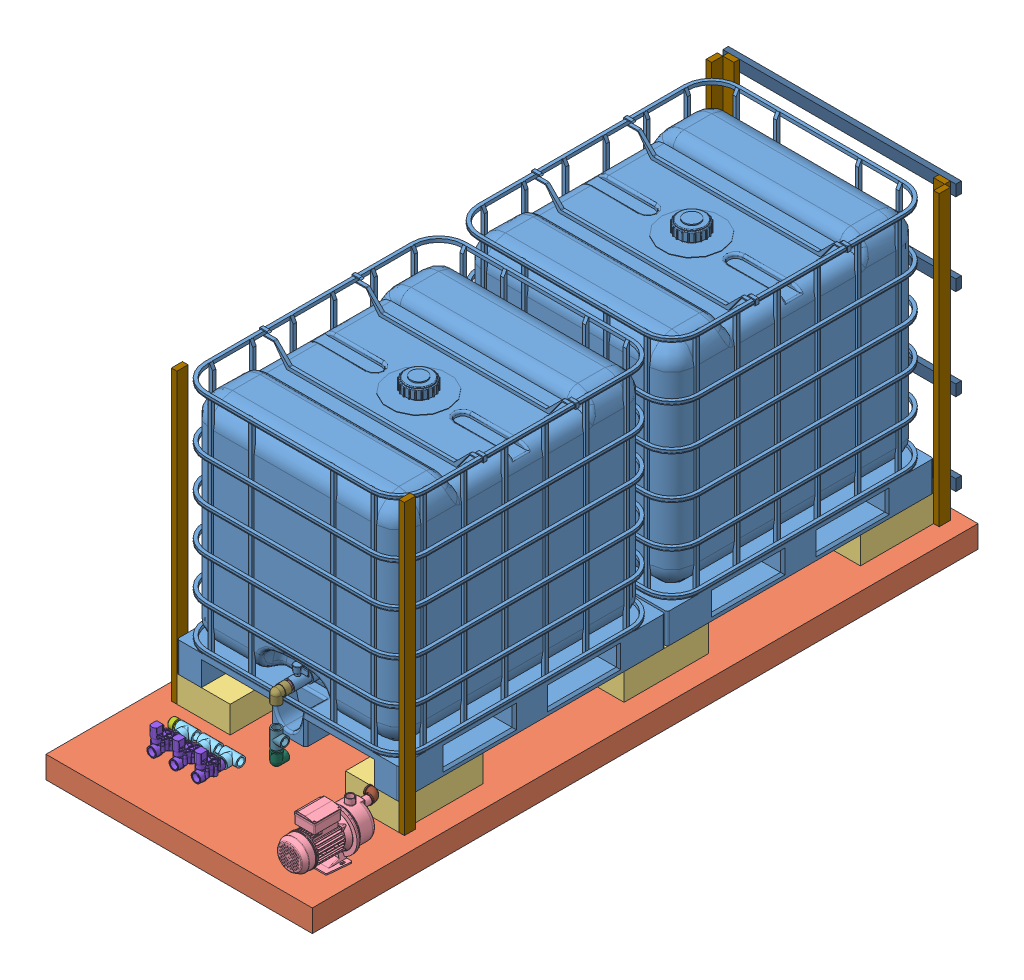
SolidWorks assembly zlozony_zbiornik, configuration Domyślna. Lengths in mm.
Overall size (1200 1400 3000).
43 component instances, 15 part files, 91 mates.
Components (placement in the parent):
- zbiornik_1000L-3: zbiornik_1000L [Domyślna] at (-84.7782 -19.1677 1200.0339) size (1010 1160 1200.03)
- zbiornik_1000L-4: zbiornik_1000L [Domyślna] at (-68.0731 -19.1677 -237.8252) x (-1 0 0) z (0 0 -1) size (1010 1160 1200.03)
- podstawa_zbiornikow-1: podstawa_zbiornikow [Domyślna] at (-76.4256 -772.0394 676.1044) x (0 0 -1) z (1 0 0) size (3000 100 1200)
- bloczek_fundamentowy-1: bloczek_fundamentowy [Domyślna] at (-456.4256 -672.0394 -583.8956) x (0 0 -1) z (1 0 0) size (380 120 240)
- bloczek_fundamentowy-2: bloczek_fundamentowy [Domyślna] at (303.5744 -672.0394 -583.8956) x (0 0 -1) z (1 0 0) size (380 120 240)
- bloczek_fundamentowy-3: bloczek_fundamentowy [Domyślna] at (303.5744 -672.0394 1496.1044) x (0 0 -1) z (1 0 0) size (380 120 240)
- bloczek_fundamentowy-4: bloczek_fundamentowy [Domyślna] at (303.5744 -672.0394 481.1044) x (0 0 -1) z (1 0 0) size (380 120 240)
- bloczek_fundamentowy-5: bloczek_fundamentowy [Domyślna] at (-456.4256 -672.0394 1496.1044) x (0 0 -1) z (1 0 0) size (380 120 240)
- bloczek_fundamentowy-6: bloczek_fundamentowy [Domyślna] at (-456.4256 -672.0394 481.1044) x (0 0 -1) z (1 0 0) size (380 120 240)
- WJ 202-x-1: WJ 202-x [Default] at (373.8254 -573.0394 1909.6044) x (0 0 1) z (-1 0 0) size (354 228.5 184)
- Trojnik_32_gz1-1: Trojnik_32_gz1 [Default] at (-94.2256 -519.8394 1919.1044) x (0 0 1) z (-1 0 0) size (88 48 77)
  - 300125171_01-1: 300125171_01 [Default] at origin size (68 48 77)
  - 300125171_02-1: 300125171_02 [Default] at origin size (38 43 43)
- Trojnik_32_gz1-2: Trojnik_32_gz1 [Default] at (-194.2256 -519.8394 1919.1044) x (0 0 1) z (-1 0 0) size (88 48 77)
  - 300125171_01-1: 300125171_01 [Default] at origin size (68 48 77)
  - 300125171_02-1: 300125171_02 [Default] at origin size (38 43 43)
- Trojnik_32_gz1-3: Trojnik_32_gz1 [Default] at (-294.2256 -519.8394 1919.1044) x (0 0 1) z (-1 0 0) size (88 48 77)
  - 300125171_01-1: 300125171_01 [Default] at origin size (68 48 77)
  - 300125171_02-1: 300125171_02 [Default] at origin size (38 43 43)
- zaslepka_32-1: zaslepka_32 [Default] at (-342.7256 -519.8394 1919.1044) size (31 43 43)
- DV100-1: DV100 [Domyślna] at (-94.2256 -519.8394 2028.1044) x (0 0 -1) z (1 0 0) size (113 119.31 83.38)
- DV100-2: DV100 [Domyślna] at (-194.2256 -519.8394 2028.1044) x (0 0 -1) z (1 0 0) size (113 119.31 83.38)
- DV100-3: DV100 [Domyślna] at (-294.2256 -519.8394 2028.1044) x (0 0 -1) z (1 0 0) size (113 119.31 83.38)
- Łata25x50^zlozony_zbiornik-1: Łata25x50^zlozony_zbiornik [Domyślna] at (-56.8231 -672.0394 651.9457) x (0 0 -1) z (0 1 0) size (25 50 1300) (virtual)
- Łata25x50^zlozony_zbiornik-2: Łata25x50^zlozony_zbiornik [Domyślna] at (893.1769 -672.0394 651.9457) x (0 0 -1) z (0 1 0) size (25 50 1300) (virtual)
- Łata25x50^zlozony_zbiornik-3: Łata25x50^zlozony_zbiornik [Domyślna] at (-1002.267 -672.0394 -254.2931) x (1 0 0) z (0 1 0) size (25 50 1300) (virtual)
- Łata25x50^zlozony_zbiornik-4: Łata25x50^zlozony_zbiornik [Domyślna] at (-2027.267 -672.0394 -254.2931) x (1 0 0) z (0 1 0) size (25 50 1300) (virtual)
- Łata25x50_pozioma^zlozony_zbiornik-1: Łata25x50_pozioma^zlozony_zbiornik [Domyślna] at (893.1769 -672.0394 -798.8956) x (0 -1 0) z (0 0 -1) size (50 1050 25) (virtual)
- Łata25x50_pozioma^zlozony_zbiornik-2: Łata25x50_pozioma^zlozony_zbiornik [Domyślna] at (893.1769 -302.0394 -798.8956) x (0 -1 0) z (0 0 -1) size (50 1050 25) (virtual)
- Łata25x50_pozioma^zlozony_zbiornik-3: Łata25x50_pozioma^zlozony_zbiornik [Domyślna] at (893.1769 107.9606 -798.8956) x (0 -1 0) z (0 0 -1) size (50 1050 25) (virtual)
- Łata25x50_pozioma^zlozony_zbiornik-4: Łata25x50_pozioma^zlozony_zbiornik [Domyślna] at (893.1769 477.9606 -798.8956) x (0 -1 0) z (0 0 -1) size (50 1050 25) (virtual)
- Łata25x50^zlozony_zbiornik-5: Łata25x50^zlozony_zbiornik [Domyślna] at (849.4157 -672.0394 1166.5018) x (-1 0 0) z (0 1 0) size (25 50 1300) (virtual)
- Łata25x50^zlozony_zbiornik-6: Łata25x50^zlozony_zbiornik [Domyślna] at (-1002.267 -672.0394 2155.7069) x (1 0 0) z (0 1 0) size (25 50 1300) (virtual)
- 90° Elbow G 1 SS-2: 90° Elbow G 1 SS [Default] at (335.8254 -524.5394 1737.6044) x (0 0 1) z (0 1 0) size (59.19 59.2 40.8)
- kolano_32_gz1-2: kolano_32_gz1 [Default] at (-76.4256 -388.5394 1737.6044) x (0 0 -1) z (0 1 0) size (88 48 60.5)
  - 300125158_01-1: 300125158_01 [Default] at origin size (68 48 60.5)
  - 300125158_02-1: 300125158_02 [Default] at origin size (38 43 43)
- trojnik_32-3: trojnik_32 [Default] at (-76.4256 -524.5394 1737.6044) x (1 0 0) z (0 1 0) size (60 43 77)
- kolano_32_gz1-3: kolano_32_gz1 [Default] at (-76.4256 -388.5394 -775.3956) x (0 0 1) z (0 1 0) size (88 48 60.5)
  - 300125158_01-1: 300125158_01 [Default] at origin size (68 48 60.5)
  - 300125158_02-1: 300125158_02 [Default] at origin size (38 43 43)
- kolano_32-9: kolano_32 [Default] at (-76.4256 -574.8405 -775.3956) x (0 0 1) z (0 -1 0) size (59.8 43.6 59.8)
- kolano_32-10: kolano_32 [Default] at (-76.4256 -612.8405 1699.6044) x (0 1 0) z (0 0 1) size (59.8 43.6 59.8)
Mates (geometry in assembly coordinates):
- Wspólnie21: coincident anti-aligned: plane of podstawa_zbiornikow-1 through (-76.4256 -672.0394 676.1044) normal (0 1 0); plane of bloczek_fundamentowy-5 through (-456.4256 -672.0394 1496.1044) normal (0 -1 0)
- Wspólnie25: coincident anti-aligned: plane of podstawa_zbiornikow-1 through (-76.4256 -672.0394 676.1044) normal (0 1 0); plane of bloczek_fundamentowy-1 through (-456.4256 -672.0394 -583.8956) normal (0 -1 0)
- Wspólnie26: coincident anti-aligned: plane of podstawa_zbiornikow-1 through (-76.4256 -672.0394 676.1044) normal (0 1 0); plane of bloczek_fundamentowy-6 through (-456.4256 -672.0394 481.1044) normal (0 -1 0)
- Wspólnie27: coincident anti-aligned: plane of podstawa_zbiornikow-1 through (-76.4256 -672.0394 676.1044) normal (0 1 0); plane of bloczek_fundamentowy-5 through (-456.4256 -672.0394 1496.1044) normal (0 -1 0)
- Wspólnie28: coincident anti-aligned: plane of podstawa_zbiornikow-1 through (-76.4256 -672.0394 676.1044) normal (0 1 0); plane of bloczek_fundamentowy-2 through (303.5744 -672.0394 -583.8956) normal (0 -1 0)
- Wspólnie29: coincident anti-aligned: plane of podstawa_zbiornikow-1 through (-76.4256 -672.0394 676.1044) normal (0 1 0); plane of bloczek_fundamentowy-4 through (303.5744 -672.0394 481.1044) normal (0 -1 0)
- Wspólnie30: coincident anti-aligned: plane of podstawa_zbiornikow-1 through (-76.4256 -672.0394 676.1044) normal (0 1 0); plane of bloczek_fundamentowy-3 through (303.5744 -672.0394 1496.1044) normal (0 -1 0)
- Szerokość1: width anti-aligned: plane of podstawa_zbiornikow-1 through (523.5744 -672.0394 2176.1044) normal (1 0 0); plane of podstawa_zbiornikow-1 through (-676.4256 -672.0394 2176.1044) normal (-1 0 0); plane of zbiornik_1000L-1/zbiornik_1000L.stp-1/PALLET.stp-1 through (-576.4256 -417.0394 486.1044) normal (-1 0 0); plane of zbiornik_1000L-1/zbiornik_1000L.stp-1/PALLET.stp-1 through (423.5744 -552.0394 486.1044) normal (1 0 0)
- Wspólnie31: coincident anti-aligned: plane of bloczek_fundamentowy-4 through (303.5744 -552.0394 481.1044) normal (0 1 0); plane of zbiornik_1000L-1/zbiornik_1000L.stp-1/PALLET.stp-1 through (-576.4256 -552.0394 486.1044) normal (0 -1 0)
- Wspólnie32: coincident aligned: plane of bloczek_fundamentowy-4 through (423.5744 -552.0394 671.1044) normal (1 0 0); plane of zbiornik_1000L-1/zbiornik_1000L.stp-1/PALLET.stp-1 through (423.5744 -552.0394 486.1044) normal (1 0 0)
- Wspólnie34: coincident aligned: plane of bloczek_fundamentowy-3 through (423.5744 -552.0394 1686.1044) normal (1 0 0); plane of zbiornik_1000L-1/zbiornik_1000L.stp-1/PALLET.stp-1 through (423.5744 -552.0394 486.1044) normal (1 0 0)
- Wspólnie35: coincident aligned: plane of bloczek_fundamentowy-3 through (423.5744 -552.0394 1686.1044) normal (0 0 1); plane of zbiornik_1000L-1/zbiornik_1000L.stp-1/PALLET.stp-1 through (-76.4256 -484.5394 1686.1044) normal (0 0 1)
- Wspólnie39: coincident aligned: plane of bloczek_fundamentowy-6 through (-576.4256 -552.0394 671.1044) normal (-1 0 0); plane of zbiornik_1000L-1/zbiornik_1000L.stp-1/PALLET.stp-1 through (-576.4256 -417.0394 486.1044) normal (-1 0 0)
- Wspólnie40: coincident aligned: plane of bloczek_fundamentowy-5 through (-576.4256 -552.0394 1686.1044) normal (-1 0 0); plane of zbiornik_1000L-1/zbiornik_1000L.stp-1/PALLET.stp-1 through (-576.4256 -417.0394 486.1044) normal (-1 0 0)
- Wspólnie41: coincident aligned: plane of bloczek_fundamentowy-5 through (-336.4256 -552.0394 1686.1044) normal (0 0 1); plane of zbiornik_1000L-1/zbiornik_1000L.stp-1/PALLET.stp-1 through (-76.4256 -484.5394 1686.1044) normal (0 0 1)
- Odległość15: distance = 50 mm aligned: plane of bloczek_fundamentowy-2 through (423.5744 -552.0394 -773.8956) normal (0 0 -1); plane of podstawa_zbiornikow-1 through (523.5744 -672.0394 -823.8956) normal (0 0 -1)
- Koncentryczne35: concentric aligned: cylinder of Trojnik_32_gz1-1/300125171_01-1 through (-94.2256 -519.8394 1919.1044) axis (1 0 0) radius 22; cylinder of Trojnik_32_gz1-2/300125171_01-1 through (-194.2256 -519.8394 1919.1044) axis (1 0 0) radius 22
- Odległość25: distance = 100 mm: cylinder of Trojnik_32_gz1-2/300125171_02-1 through (-194.2256 -519.8394 1975.1044) axis (0 0 -1) radius 16.625; cylinder of Trojnik_32_gz1-1/300125171_02-1 through (-94.2256 -519.8394 1975.1044) axis (0 0 -1) radius 16.625
- Koncentryczne37: concentric aligned: cylinder of Trojnik_32_gz1-2/300125171_01-1 through (-194.2256 -519.8394 1919.1044) axis (1 0 0) radius 22; cylinder of Trojnik_32_gz1-3/300125171_01-1 through (-294.2256 -519.8394 1919.1044) axis (1 0 0) radius 22
- Odległość26: distance = 100 mm: cylinder of Trojnik_32_gz1-2/300125171_02-1 through (-194.2256 -519.8394 1975.1044) axis (0 0 -1) radius 16.625; cylinder of Trojnik_32_gz1-3/300125171_02-1 through (-294.2256 -519.8394 1975.1044) axis (0 0 -1) radius 16.625
- Koncentryczne39: concentric aligned: cylinder of Trojnik_32_gz1-3/300125171_01-1 through (-294.2256 -519.8394 1919.1044) axis (1 0 0) radius 22; cylinder of zaslepka_32-1 through (-352.7256 -519.8394 1919.1044) axis (1 0 0) radius 21.5
- Odległość27: distance = 10 mm anti-aligned: plane of Trojnik_32_gz1-3/300125171_01-1 through (-332.7256 -519.8394 1919.1044) normal (-1 0 0); plane of zaslepka_32-1 through (-342.7256 -519.8394 1919.1044) normal (1 0 0)
- Wspólnie42: coincident anti-aligned: plane of zbiornik_1000L-3 through (-576.4256 -552.0394 486.1044) normal (0 -1 0); plane of bloczek_fundamentowy-5 through (-456.4256 -552.0394 1496.1044) normal (0 1 0)
- Wspólnie44: coincident aligned: plane of zbiornik_1000L-3 through (-576.4256 -417.0394 486.1044) normal (-1 0 0); plane of bloczek_fundamentowy-6 through (-576.4256 -552.0394 671.1044) normal (-1 0 0)
- Wspólnie45: coincident aligned: plane of zbiornik_1000L-3 through (423.5744 -552.0394 486.1044) normal (1 0 0); plane of bloczek_fundamentowy-4 through (423.5744 -552.0394 671.1044) normal (1 0 0)
- Odległość28: distance = 10 mm anti-aligned: plane of zbiornik_1000L-3 through (-76.4256 -484.5394 486.1044) normal (0 0 -1); plane of zbiornik_1000L-4 through (-76.4256 -484.5394 476.1044) normal (0 0 1)
- Wspólnie46: coincident aligned: plane of zbiornik_1000L-3 through (423.5744 -552.0394 486.1044) normal (1 0 0); plane of zbiornik_1000L-4 through (423.5744 -417.0394 476.1044) normal (1 0 0)
- Wspólnie47: coincident aligned: plane of zbiornik_1000L-4 through (423.5744 -417.0394 476.1044) normal (1 0 0); plane of bloczek_fundamentowy-4 through (423.5744 -552.0394 671.1044) normal (1 0 0)
- Szerokość6: width anti-aligned: plane of zbiornik_1000L-3 through (423.5744 -442.0394 696.1044) normal (0 0 1); plane of zbiornik_1000L-4 through (-576.4256 -442.0394 266.1044) normal (0 0 -1); plane of bloczek_fundamentowy-4 through (423.5744 -552.0394 291.1044) normal (0 0 -1); plane of bloczek_fundamentowy-4 through (423.5744 -552.0394 671.1044) normal (0 0 1)
- Wspólnie49: coincident anti-aligned: plane of zbiornik_1000L-4 through (423.5744 -552.0394 476.1044) normal (0 -1 0); plane of bloczek_fundamentowy-4 through (303.5744 -552.0394 481.1044) normal (0 1 0)
- Wspólnie50: coincident aligned: plane of zbiornik_1000L-3 through (-76.4256 -484.5394 1686.1044) normal (0 0 1); plane of bloczek_fundamentowy-5 through (-336.4256 -552.0394 1686.1044) normal (0 0 1)
- Wspólnie51: coincident aligned: plane of zbiornik_1000L-3 through (-76.4256 -484.5394 1686.1044) normal (0 0 1); plane of bloczek_fundamentowy-3 through (423.5744 -552.0394 1686.1044) normal (0 0 1)
- Szerokość7: width anti-aligned: plane of zbiornik_1000L-3 through (423.5744 -442.0394 696.1044) normal (0 0 1); plane of zbiornik_1000L-4 through (-576.4256 -442.0394 266.1044) normal (0 0 -1); plane of bloczek_fundamentowy-6 through (-336.4256 -552.0394 291.1044) normal (0 0 -1); plane of bloczek_fundamentowy-6 through (-336.4256 -552.0394 671.1044) normal (0 0 1)
- Wspólnie53: coincident aligned: plane of zbiornik_1000L-3 through (-576.4256 -417.0394 486.1044) normal (-1 0 0); plane of bloczek_fundamentowy-5 through (-576.4256 -552.0394 1686.1044) normal (-1 0 0)
- Wspólnie54: coincident aligned: plane of zbiornik_1000L-4 through (-576.4256 -552.0394 476.1044) normal (-1 0 0); plane of bloczek_fundamentowy-1 through (-576.4256 -552.0394 -393.8956) normal (-1 0 0)
- Wspólnie57: coincident aligned: plane of zbiornik_1000L-4 through (423.5744 -417.0394 476.1044) normal (1 0 0); plane of bloczek_fundamentowy-2 through (423.5744 -552.0394 -393.8956) normal (1 0 0)
- Wspólnie58: coincident aligned: plane of zbiornik_1000L-3 through (423.5744 -552.0394 486.1044) normal (1 0 0); plane of bloczek_fundamentowy-3 through (423.5744 -552.0394 1686.1044) normal (1 0 0)
- Wspólnie59: coincident aligned: plane of zbiornik_1000L-3 through (-76.4256 -484.5394 1686.1044) normal (0 0 1); plane of bloczek_fundamentowy-3 through (423.5744 -552.0394 1686.1044) normal (0 0 1)
- Szerokość8: width anti-aligned: plane of podstawa_zbiornikow-1 through (523.5744 -672.0394 2176.1044) normal (1 0 0); plane of podstawa_zbiornikow-1 through (-676.4256 -672.0394 2176.1044) normal (-1 0 0); plane of bloczek_fundamentowy-1 through (-576.4256 -552.0394 -393.8956) normal (-1 0 0); plane of bloczek_fundamentowy-2 through (423.5744 -552.0394 -393.8956) normal (1 0 0)
- Koncentryczne42: concentric anti-aligned: cylinder of Trojnik_32_gz1-1/300125171_02-1 through (-94.2256 -519.8394 1975.1044) axis (0 0 -1) radius 16.625; cylinder of DV100-1 through (-94.2256 -519.8394 3028.1044) axis (0 0 1) radius 21.463
- Odległość31: distance = 5 mm anti-aligned: plane of Trojnik_32_gz1-1/300125171_01-1 through (-94.2256 -519.8394 1965.1044) normal (0 0 1); plane of DV100-1 through (-94.2256 -519.8394 1970.1044) normal (0 0 -1)
- Koncentryczne43: concentric anti-aligned: cylinder of Trojnik_32_gz1-2/300125171_02-1 through (-194.2256 -519.8394 1975.1044) axis (0 0 -1) radius 16.625; cylinder of DV100-2 through (-194.2256 -519.8394 3028.1044) axis (0 0 1) radius 21.463
- Koncentryczne44: concentric anti-aligned: cylinder of Trojnik_32_gz1-3/300125171_02-1 through (-294.2256 -519.8394 1975.1044) axis (0 0 -1) radius 16.625; cylinder of DV100-3 through (-294.2256 -519.8394 3028.1044) axis (0 0 1) radius 21.463
- Odległość32: distance = 5 mm anti-aligned: plane of DV100-2 through (-194.2256 -519.8394 1970.1044) normal (0 0 -1); plane of Trojnik_32_gz1-2/300125171_01-1 through (-194.2256 -519.8394 1965.1044) normal (0 0 1)
- Odległość33: distance = 5 mm anti-aligned: plane of Trojnik_32_gz1-3/300125171_01-1 through (-294.2256 -519.8394 1965.1044) normal (0 0 1); plane of DV100-3 through (-294.2256 -519.8394 1970.1044) normal (0 0 -1)
- Wspólnie63: coincident anti-aligned: plane of podstawa_zbiornikow-1 through (-76.4256 -672.0394 676.1044) normal (0 1 0); plane of Łata25x50^zlozony_zbiornik-2 through (893.1769 -672.0394 651.9457) normal (0 -1 0)
- Wspólnie64: coincident anti-aligned: plane of bloczek_fundamentowy-2 through (423.5744 -552.0394 -773.8956) normal (0 0 -1); plane of Łata25x50^zlozony_zbiornik-2 through (373.5744 627.9606 -773.8956) normal (0 0 1)
- Wspólnie65: coincident aligned: plane of bloczek_fundamentowy-2 through (423.5744 -552.0394 -393.8956) normal (1 0 0); plane of Łata25x50^zlozony_zbiornik-2 through (423.5744 627.9606 -773.8956) normal (1 0 0)
- Wspólnie67: coincident anti-aligned: plane of bloczek_fundamentowy-1 through (-336.4256 -552.0394 -773.8956) normal (0 0 -1); plane of Łata25x50^zlozony_zbiornik-1 through (-576.4256 627.9606 -773.8956) normal (0 0 1)
- Wspólnie68: coincident anti-aligned: plane of podstawa_zbiornikow-1 through (-76.4256 -672.0394 676.1044) normal (0 1 0); plane of Łata25x50^zlozony_zbiornik-1 through (-56.8231 -672.0394 651.9457) normal (0 -1 0)
- Wspólnie69: coincident aligned: plane of bloczek_fundamentowy-1 through (-576.4256 -552.0394 -393.8956) normal (-1 0 0); plane of Łata25x50^zlozony_zbiornik-1 through (-576.4256 627.9606 -773.8956) normal (-1 0 0)
- Wspólnie70: coincident anti-aligned: plane of bloczek_fundamentowy-2 through (423.5744 -552.0394 -393.8956) normal (1 0 0); plane of Łata25x50^zlozony_zbiornik-3 through (423.5744 627.9606 -773.8956) normal (-1 0 0)
- Wspólnie71: coincident anti-aligned: plane of podstawa_zbiornikow-1 through (-76.4256 -672.0394 676.1044) normal (0 1 0); plane of Łata25x50^zlozony_zbiornik-3 through (-1002.267 -672.0394 -254.2931) normal (0 -1 0)
- Wspólnie72: coincident aligned: plane of bloczek_fundamentowy-2 through (423.5744 -552.0394 -773.8956) normal (0 0 -1); plane of Łata25x50^zlozony_zbiornik-3 through (423.5744 627.9606 -773.8956) normal (0 0 -1)
- Wspólnie73: coincident anti-aligned: plane of bloczek_fundamentowy-1 through (-576.4256 -552.0394 -393.8956) normal (-1 0 0); plane of Łata25x50^zlozony_zbiornik-4 through (-576.4256 627.9606 -773.8956) normal (1 0 0)
- Wspólnie74: coincident anti-aligned: plane of podstawa_zbiornikow-1 through (-76.4256 -672.0394 676.1044) normal (0 1 0); plane of Łata25x50^zlozony_zbiornik-4 through (-2027.267 -672.0394 -254.2931) normal (0 -1 0)
- Wspólnie75: coincident aligned: plane of bloczek_fundamentowy-1 through (-336.4256 -552.0394 -773.8956) normal (0 0 -1); plane of Łata25x50^zlozony_zbiornik-4 through (-601.4256 627.9606 -773.8956) normal (0 0 -1)
- Ustalone8: in place: plane of ? through (373.5744 627.9606 -748.8956) normal (0 0 -1); plane of ? through (0 0 -748.8956) normal (0 0 -1); moOrthogonalPlaneRef_w of ? through (373.5744 627.9606 -748.8956) normal (0 0 -1); plane of ? through (0 0 -748.8956) normal (0 1 0); plane of ? through (373.5744 627.9606 -748.8956) normal (0 0 -1); plane of ? through (0 0 -748.8956) normal (-1 0 0); plane of Łata25x50^zlozony_zbiornik-2 through (373.5744 627.9606 -798.8956) normal (0 0 -1); unknown of Łata25x50_pozioma^zlozony_zbiornik-1
- Wspólnie76: coincident aligned: plane of Łata25x50^zlozony_zbiornik-2; plane of Łata25x50_pozioma^zlozony_zbiornik-1
- Wspólnie77: coincident aligned: moOrthogonalPlaneRef_w of Łata25x50^zlozony_zbiornik-2 through (893.1769 -672.0394 -798.8956) normal (-1 0 0); plane of Łata25x50_pozioma^zlozony_zbiornik-1 through (893.1769 -672.0394 -798.8956) normal (-1 0 0)
- Wspólnie78: coincident anti-aligned: moOrthogonalPlaneRef_w of Łata25x50^zlozony_zbiornik-2 through (893.1769 -672.0394 -798.8956) normal (0 1 0); plane of Łata25x50_pozioma^zlozony_zbiornik-1 through (893.1769 -672.0394 -798.8956) normal (0 -1 0)
- Odległość35: distance = 50 mm aligned: plane of bloczek_fundamentowy-2 through (423.5744 -552.0394 -773.8956) normal (0 0 -1); plane of zbiornik_1000L-4 through (-76.4256 -484.5394 -723.8956) normal (0 0 -1)
- Wspólnie79: coincident aligned: plane of bloczek_fundamentowy-1 through (-336.4256 -552.0394 -773.8956) normal (0 0 -1); plane of bloczek_fundamentowy-2 through (423.5744 -552.0394 -773.8956) normal (0 0 -1)
- Wspólnie80: coincident anti-aligned: plane of Łata25x50^zlozony_zbiornik-1 through (-576.4256 627.9606 -798.8956) normal (0 0 -1); plane of Łata25x50_pozioma^zlozony_zbiornik-4 through (893.1769 477.9606 -798.8956) normal (0 0 1)
- Wspólnie81: coincident aligned: plane of Łata25x50_pozioma^zlozony_zbiornik-1 through (-601.4256 -572.0394 -823.8956) normal (-1 0 0); plane of Łata25x50_pozioma^zlozony_zbiornik-4 through (-601.4256 577.9606 -823.8956) normal (-1 0 0)
- Wspólnie82: coincident aligned: plane of Łata25x50^zlozony_zbiornik-1 through (-56.8231 627.9606 651.9457) normal (0 1 0); plane of Łata25x50_pozioma^zlozony_zbiornik-4 through (448.5744 627.9606 -823.8956) normal (0 1 0)
- Wspólnie83: coincident anti-aligned: plane of Łata25x50^zlozony_zbiornik-1 through (-576.4256 627.9606 -798.8956) normal (0 0 -1); plane of Łata25x50_pozioma^zlozony_zbiornik-3 through (893.1769 107.9606 -798.8956) normal (0 0 1)
- Wspólnie84: coincident aligned: plane of Łata25x50_pozioma^zlozony_zbiornik-1 through (-601.4256 -572.0394 -823.8956) normal (-1 0 0); plane of Łata25x50_pozioma^zlozony_zbiornik-3 through (-601.4256 207.9606 -823.8956) normal (-1 0 0)
- Wspólnie85: coincident anti-aligned: plane of Łata25x50^zlozony_zbiornik-1 through (-576.4256 627.9606 -798.8956) normal (0 0 -1); plane of Łata25x50_pozioma^zlozony_zbiornik-2 through (893.1769 -302.0394 -798.8956) normal (0 0 1)
- Wspólnie86: coincident aligned: plane of Łata25x50_pozioma^zlozony_zbiornik-1 through (-601.4256 -572.0394 -823.8956) normal (-1 0 0); plane of Łata25x50_pozioma^zlozony_zbiornik-2 through (-601.4256 -202.0394 -823.8956) normal (-1 0 0)
- Odległość36: distance = 320 mm anti-aligned: plane of Łata25x50_pozioma^zlozony_zbiornik-3 through (448.5744 257.9606 -823.8956) normal (0 1 0); plane of Łata25x50_pozioma^zlozony_zbiornik-4 through (448.5744 577.9606 -823.8956) normal (0 -1 0)
- Odległość37: distance = 320 mm anti-aligned: plane of Łata25x50_pozioma^zlozony_zbiornik-2 through (448.5744 -202.0394 -823.8956) normal (0 -1 0); plane of Łata25x50_pozioma^zlozony_zbiornik-1 through (448.5744 -522.0394 -823.8956) normal (0 1 0)
- Wspólnie87: coincident anti-aligned: plane of bloczek_fundamentowy-5 through (-576.4256 -552.0394 1686.1044) normal (-1 0 0); plane of Łata25x50^zlozony_zbiornik-5 through (-576.4256 627.9606 1686.1044) normal (1 0 0)
- Wspólnie88: coincident anti-aligned: plane of podstawa_zbiornikow-1 through (-76.4256 -672.0394 676.1044) normal (0 1 0); plane of Łata25x50^zlozony_zbiornik-5 through (849.4157 -672.0394 1166.5018) normal (0 -1 0)
- Wspólnie89: coincident aligned: plane of bloczek_fundamentowy-5 through (-336.4256 -552.0394 1686.1044) normal (0 0 1); plane of Łata25x50^zlozony_zbiornik-5 through (-576.4256 627.9606 1686.1044) normal (0 0 1)
- Wspólnie90: coincident anti-aligned: plane of bloczek_fundamentowy-3 through (423.5744 -552.0394 1686.1044) normal (1 0 0); plane of Łata25x50^zlozony_zbiornik-6 through (423.5744 627.9606 1636.1044) normal (-1 0 0)
- Wspólnie91: coincident anti-aligned: plane of podstawa_zbiornikow-1 through (-76.4256 -672.0394 676.1044) normal (0 1 0); plane of Łata25x50^zlozony_zbiornik-6 through (-1002.267 -672.0394 2155.7069) normal (0 -1 0)
- Wspólnie92: coincident aligned: plane of bloczek_fundamentowy-3 through (423.5744 -552.0394 1686.1044) normal (0 0 1); plane of Łata25x50^zlozony_zbiornik-6 through (423.5744 627.9606 1686.1044) normal (0 0 1)
- Równolegle4: parallel aligned: plane of podstawa_zbiornikow-1 through (523.5744 -672.0394 2176.1044) normal (0 0 1); plane of WJ 202-x-1 through (325.2955 -672.0394 2017.6044) normal (0 0 1)
- Wspólnie94: coincident anti-aligned: plane of podstawa_zbiornikow-1 through (-76.4256 -672.0394 676.1044) normal (0 1 0); plane of WJ 202-x-1 through (325.2955 -672.0394 2011.6044) normal (0 -1 0)
- Wspólnie95: coincident anti-aligned: plane of WJ 202-x-1 through (373.8254 -506.5394 1775.6044) normal (0 0 -1); plane of 90° Elbow G 1 SS-2 through (373.8254 -524.5394 1775.6044) normal (0 0 1)
- Koncentryczne47: concentric anti-aligned: cylinder of WJ 202-x-1 through (373.8254 -524.5394 1775.6044) axis (0 0 -1) radius 18; cylinder of 90° Elbow G 1 SS-2 through (373.8254 -524.5394 1769.1044) axis (0 0 1) radius 20.4
- Koncentryczne48: concentric aligned: cylinder of zbiornik_1000L-3 through (-76.4256 -352.0394 1601.1044) axis (0 0 1) radius 25; cylinder of kolano_32_gz1-2/300125158_01-1 through (-76.4256 -352.0394 1705.1044) axis (0 0 1) radius 24
- Odległość38: distance = 10 mm anti-aligned: plane of zbiornik_1000L-3 through (-76.4256 -352.0394 1681.1044) normal (0 0 1); plane of kolano_32_gz1-2/300125158_01-1 through (-76.4256 -352.0394 1691.1044) normal (0 0 -1)
- Koncentryczne49: concentric aligned: cylinder of kolano_32_gz1-2/300125158_01-1 through (-76.4256 -370.2894 1737.6044) axis (0 -1 0) radius 21.5; cylinder of trojnik_32-3 through (-76.4256 -524.5394 1737.6044) axis (0 -1 0) radius 21.5
- Koncentryczne50: concentric aligned: cylinder of 90° Elbow G 1 SS-2 through (342.3254 -524.5394 1737.6044) axis (-1 0 0) radius 20.4; cylinder of trojnik_32-3 through (-57.1756 -524.5394 1737.6044) axis (-1 0 0) radius 21.5
- Koncentryczne53: concentric aligned: cylinder of zbiornik_1000L-4 through (-76.4256 -352.0394 -638.8956) axis (0 0 -1) radius 25; cylinder of kolano_32_gz1-3/300125158_01-1 through (-76.4256 -352.0394 -742.8956) axis (0 0 -1) radius 24
- Odległość39: distance = 10 mm anti-aligned: plane of zbiornik_1000L-4 through (-76.4256 -352.0394 -718.8956) normal (0 0 -1); plane of kolano_32_gz1-3/300125158_01-1 through (-76.4256 -352.0394 -728.8956) normal (0 0 1)
- Koncentryczne54: concentric anti-aligned: cylinder of kolano_32_gz1-3/300125158_01-1 through (-76.4256 -370.2894 -775.3956) axis (0 -1 0) radius 21.5; cylinder of kolano_32-9 through (-76.4256 -583.3722 -775.3956) axis (0 1 0) radius 21.5
- Koncentryczne55: concentric anti-aligned: cylinder of trojnik_32-3 through (-76.4256 -524.5394 1737.6044) axis (0 -1 0) radius 21.5; cylinder of kolano_32-10 through (-76.4256 -593.8405 1737.6044) axis (0 1 0) radius 21.5
- Koncentryczne56: concentric anti-aligned: cylinder of kolano_32-9 through (-76.4256 -612.8405 -756.3956) axis (0 0 1) radius 21.5; cylinder of kolano_32-10 through (-76.4256 -612.8405 1718.6044) axis (0 0 -1) radius 21.5
